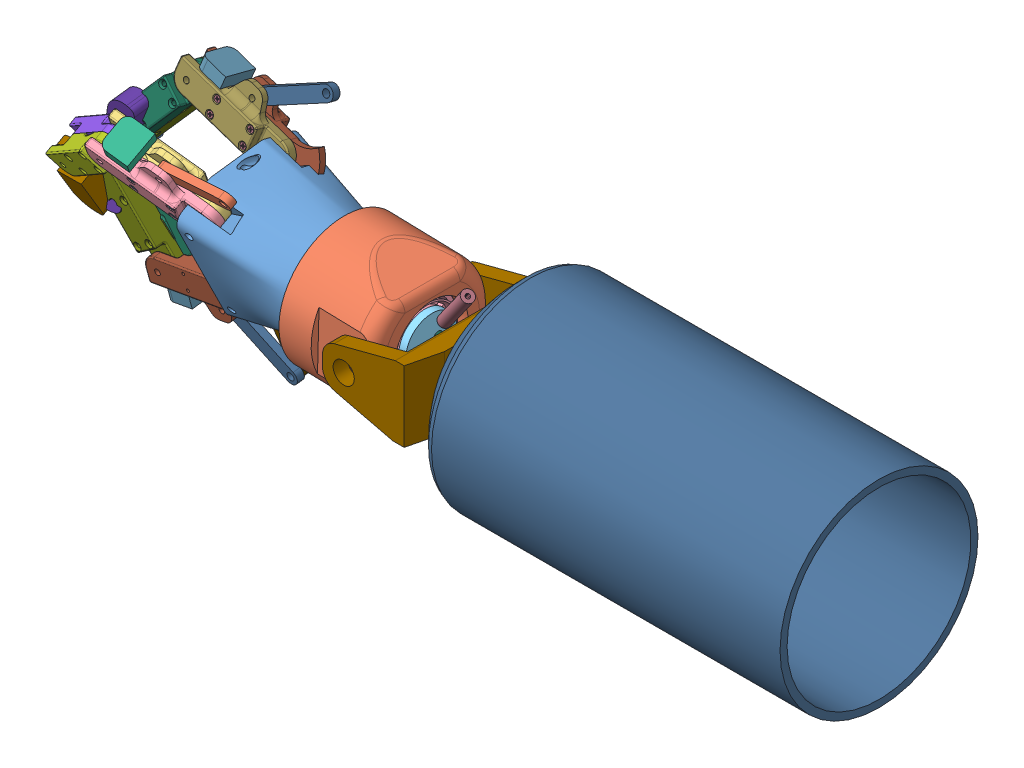
SolidWorks assembly Wrist-Rev1, configuration Default. Lengths in mm.
Overall size (584.91 244.28 159.91).
66 component instances, 31 part files, 5 mates.
Components (placement in the parent):
- handAssem^Wrist-Rev1-1: handAssem^Wrist-Rev1 [Default] at (-134.1215 -3.6591 -0.8911) x (0.999653 -0.026335 0) z (-0.003482 -0.132175 0.99122) size (188.44 172.28 105.92) (virtual)
  - Copy of hand^handAssem_Wrist-Rev1-1: Copy of hand^handAssem_Wrist-Rev1 [Default] at origin size (70.02 96.36 87.58) (virtual)
  - Copy of Finger^handAssem_Wrist-Rev1-1: Copy of Finger^handAssem_Wrist-Rev1 [Default] at (-63.4206 33.3683 25.4621) x (0.985078 0.159576 0.064473) z (0 -0.374607 0.927184) size (161.76 98.98 31.79) (virtual)
    - Part1^Copy of Finger_handAssem_Wrist-Rev1-1: Part1^Copy of Finger_handAssem_Wrist-Rev1 [Default] at (-16.5165 25.6409 -2) x (0.998962 0.045543 0) z (0 0 1) size (57.61 9.59 5) (virtual)
    - AssemFP3^Copy of Finger_handAssem_Wrist-Rev1-1: AssemFP3^Copy of Finger_handAssem_Wrist-Rev1 [Default] at (-63.9805 30.7815 -12) x (0.901133 -0.433542 0) z (0 0 1) size (80 31.95 25) (virtual)
      - Copy of SecondSideDoubleFP3^AssemFP3_Copy of Finger_handAssem_Wrist-Rev1-1: Copy of SecondSideDoubleFP3^AssemFP3_Copy of Finger_handAssem_Wrist-Rev1 [Default] at origin size (80 31.95 13.34) (virtual)
      - Copy of FirstSideDoubleFP3^AssemFP3_Copy of Finger_handAssem_Wrist-Rev1-1: Copy of FirstSideDoubleFP3^AssemFP3_Copy of Finger_handAssem_Wrist-Rev1 [Default] at (0 0 25) size (80 31.95 13.34) (virtual)
      - Copy of Self Tapping Cross recessed Screw 4Plastic^AssemFP3_Copy of Finger_handAssem_Wrist-Rev1-1: Copy of Self Tapping Cross recessed Screw 4Plastic^AssemFP3_Copy of Finger_handAssem_Wrist-Rev1 [Self Tap. Cross recessed Screw 2.6x16mm] at (30 -5.5 24.6) x (0 0 -1) z (0.511013 -0.859573 0) size (16 4.2 4.2) (virtual)
      - Copy of Self Tapping Cross recessed Screw 4Plastic^AssemFP3_Copy of Finger_handAssem_Wrist-Rev1-2: Copy of Self Tapping Cross recessed Screw 4Plastic^AssemFP3_Copy of Finger_handAssem_Wrist-Rev1 [Self Tap. Cross recessed Screw 2.6x16mm] at (30 4.7 24.6) x (0 0 -1) z (0.511013 -0.859573 0) size (16 4.2 4.2) (virtual)
      - Copy of Self Tapping Cross recessed Screw 4Plastic^AssemFP3_Copy of Finger_handAssem_Wrist-Rev1-3: Copy of Self Tapping Cross recessed Screw 4Plastic^AssemFP3_Copy of Finger_handAssem_Wrist-Rev1 [Self Tap. Cross recessed Screw 2.6x16mm] at (55.5 -5.5 24.6) x (0 0 -1) z (0.511013 -0.859573 0) size (16 4.2 4.2) (virtual)
      - Copy of Self Tapping Cross recessed Screw 4Plastic^AssemFP3_Copy of Finger_handAssem_Wrist-Rev1-4: Copy of Self Tapping Cross recessed Screw 4Plastic^AssemFP3_Copy of Finger_handAssem_Wrist-Rev1 [Self Tap. Cross recessed Screw 2.6x16mm] at (55.5 5.5 24.6) x (0 0 -1) z (0.511013 -0.859573 0) size (16 4.2 4.2) (virtual)
      - Copy of Part2^AssemFP3_Copy of Finger_handAssem_Wrist-Rev1-1: Copy of Part2^AssemFP3_Copy of Finger_handAssem_Wrist-Rev1 [Default] at (9.0118 9 22.7194) x (0.006732 0 -0.999977) z (0.999977 0 0.006732) size (22 8 19) (virtual)
    - AssemFP2^Copy of Finger_handAssem_Wrist-Rev1-1: AssemFP2^Copy of Finger_handAssem_Wrist-Rev1 [Default] at (-31.4624 86.5481 -31.1774) x (0.884286 0.466511 0.020138) z (-0.063233 0.076906 0.995031) size (81.78 27.56 27.59) (virtual)
      - Copy of FirstSideDoubleFP2^AssemFP2_Copy of Finger_handAssem_Wrist-Rev1-1: Copy of FirstSideDoubleFP2^AssemFP2_Copy of Finger_handAssem_Wrist-Rev1 [Default] at (-119.2204 -52.1061 42.2073) x (0.995783 0.091045 -0.011232) z (0.020138 -0.097506 0.995031) size (80 18.36 12.86) (virtual)
      - Copy of Copy of FirstSideDoubleFP2^AssemFP2_Copy of Finger_handAssem_Wrist-Rev1-1: Copy of Copy of FirstSideDoubleFP2^AssemFP2_Copy of Finger_handAssem_Wrist-Rev1 [Default] at (-119.7239 -49.6685 17.3316) x (0.995783 0.091045 -0.011232) z (0.020138 -0.097506 0.995031) size (80 18 12.5) (virtual)
    - AssemFP1^Copy of Finger_handAssem_Wrist-Rev1-1: AssemFP1^Copy of Finger_handAssem_Wrist-Rev1 [Default] at (-46.7906 101.0539 0) x (0.072186 0.997391 0) z (0 0 1) size (49.14 18 13.29) (virtual)
      - Copy of Part4^AssemFP1_Copy of Finger_handAssem_Wrist-Rev1-1: Copy of Part4^AssemFP1_Copy of Finger_handAssem_Wrist-Rev1 [Default] at (-121.6487 44.1587 14.7911) size (49.14 18 13.29) (virtual)
  - Copy (2) of Finger^handAssem_Wrist-Rev1-1: Copy (2) of Finger^handAssem_Wrist-Rev1 [Default] at (-65.476 37.9304 -28.3284) x (0.903748 0.396895 -0.160356) z (0 0.374607 0.927184) size (164.28 92.56 31.79) (virtual)
    - Part1^Copy (2) of Finger_handAssem_Wrist-Rev1-1: Part1^Copy (2) of Finger_handAssem_Wrist-Rev1 [Default] at (-10.8234 25.7812 -2.0514) x (0.998962 0.045543 0) z (0 0 1) size (57.61 9.59 5) (virtual)
    - AssemFP3^Copy (2) of Finger_handAssem_Wrist-Rev1-1: AssemFP3^Copy (2) of Finger_handAssem_Wrist-Rev1 [Default] at (-55.9504 41.3634 -12.0514) x (0.781947 -0.623344 0) z (0 0 1) size (96 40.28 25) (virtual)
      - Copy of SecondSideDoubleFP3^AssemFP3_Copy (2) of Finger_handAssem_Wrist-Rev1-1: Copy of SecondSideDoubleFP3^AssemFP3_Copy (2) of Finger_handAssem_Wrist-Rev1 [Default] at origin size (96 40.28 13.34) (virtual)
      - Copy of FirstSideDoubleFP3^AssemFP3_Copy (2) of Finger_handAssem_Wrist-Rev1-1: Copy of FirstSideDoubleFP3^AssemFP3_Copy (2) of Finger_handAssem_Wrist-Rev1 [Default] at (0 0 25) size (80 31.95 13.34) (virtual)
      - Copy of Self Tapping Cross recessed Screw 4Plastic^AssemFP3_Copy (2) of Finger_handAssem_Wrist-Rev1-1: Copy of Self Tapping Cross recessed Screw 4Plastic^AssemFP3_Copy (2) of Finger_handAssem_Wrist-Rev1 [Self Tap. Cross recessed Screw 2.6x16mm] at (30 -5.5 24.6) x (0 0 -1) z (0.511013 -0.859573 0) size (16 4.2 4.2) (virtual)
      - Copy of Self Tapping Cross recessed Screw 4Plastic^AssemFP3_Copy (2) of Finger_handAssem_Wrist-Rev1-2: Copy of Self Tapping Cross recessed Screw 4Plastic^AssemFP3_Copy (2) of Finger_handAssem_Wrist-Rev1 [Self Tap. Cross recessed Screw 2.6x16mm] at (30 4.7 24.6) x (0 0 -1) z (0.511013 -0.859573 0) size (16 4.2 4.2) (virtual)
      - Copy of Self Tapping Cross recessed Screw 4Plastic^AssemFP3_Copy (2) of Finger_handAssem_Wrist-Rev1-3: Copy of Self Tapping Cross recessed Screw 4Plastic^AssemFP3_Copy (2) of Finger_handAssem_Wrist-Rev1 [Self Tap. Cross recessed Screw 2.6x16mm] at (55.5 -5.5 24.6) x (0 0 -1) z (0.511013 -0.859573 0) size (16 4.2 4.2) (virtual)
      - Copy of Self Tapping Cross recessed Screw 4Plastic^AssemFP3_Copy (2) of Finger_handAssem_Wrist-Rev1-4: Copy of Self Tapping Cross recessed Screw 4Plastic^AssemFP3_Copy (2) of Finger_handAssem_Wrist-Rev1 [Self Tap. Cross recessed Screw 2.6x16mm] at (55.5 5.5 24.6) x (0 0 -1) z (0.511013 -0.859573 0) size (16 4.2 4.2) (virtual)
      - Copy of Part2^AssemFP3_Copy (2) of Finger_handAssem_Wrist-Rev1-1: Copy of Part2^AssemFP3_Copy (2) of Finger_handAssem_Wrist-Rev1 [Default] at (9.0118 9 22.7194) x (0.006732 0 -0.999977) z (0.999977 0 0.006732) size (22 8 19) (virtual)
    - AssemFP2^Copy (2) of Finger_handAssem_Wrist-Rev1-1: AssemFP2^Copy (2) of Finger_handAssem_Wrist-Rev1 [Default] at (-18.1675 92.417 -31.2288) x (0.929732 0.367687 0.020138) z (-0.054504 0.083321 0.995031) size (81.78 27.56 27.59) (virtual)
      - Copy of FirstSideDoubleFP2^AssemFP2_Copy (2) of Finger_handAssem_Wrist-Rev1-1: Copy of FirstSideDoubleFP2^AssemFP2_Copy (2) of Finger_handAssem_Wrist-Rev1 [Default] at (-119.2204 -52.1061 42.2073) x (0.995783 0.091045 -0.011232) z (0.020138 -0.097506 0.995031) size (80 18.36 12.86) (virtual)
      - Copy of Copy of FirstSideDoubleFP2^AssemFP2_Copy (2) of Finger_handAssem_Wrist-Rev1-1: Copy of Copy of FirstSideDoubleFP2^AssemFP2_Copy (2) of Finger_handAssem_Wrist-Rev1 [Default] at (-119.7239 -49.6685 17.3316) x (0.995783 0.091045 -0.011232) z (0.020138 -0.097506 0.995031) size (80 18 12.5) (virtual)
    - AssemFP1^Copy (2) of Finger_handAssem_Wrist-Rev1-1: AssemFP1^Copy (2) of Finger_handAssem_Wrist-Rev1 [Default] at (-27.2302 105.0249 -0.0514) x (0.225639 0.974211 0) z (0 0 1) size (49.14 18 13.29) (virtual)
      - Copy of Part4^AssemFP1_Copy (2) of Finger_handAssem_Wrist-Rev1-1: Copy of Part4^AssemFP1_Copy (2) of Finger_handAssem_Wrist-Rev1 [Default] at (-121.6487 44.1587 14.7911) size (49.14 18 13.29) (virtual)
  - Copy (2) of Finger^handAssem_Wrist-Rev1-2: Copy (2) of Finger^handAssem_Wrist-Rev1 [Default] at (-64.0753 -41.2434 0.4486) x (0.9011 -0.433611 0) z (0 0 -1) size (164.28 92.56 31.79) (virtual)
    - Part1^Copy (2) of Finger_handAssem_Wrist-Rev1-1: Part1^Copy (2) of Finger_handAssem_Wrist-Rev1 [Default] at (-10.8234 25.7812 -2.0514) x (0.998962 0.045543 0) z (0 0 1) size (57.61 9.59 5) (virtual)
    - AssemFP3^Copy (2) of Finger_handAssem_Wrist-Rev1-1: AssemFP3^Copy (2) of Finger_handAssem_Wrist-Rev1 [Default] at (-55.9504 41.3634 -12.0514) x (0.781947 -0.623344 0) z (0 0 1) size (96 40.28 25) (virtual)
      - Copy of SecondSideDoubleFP3^AssemFP3_Copy (2) of Finger_handAssem_Wrist-Rev1-1: Copy of SecondSideDoubleFP3^AssemFP3_Copy (2) of Finger_handAssem_Wrist-Rev1 [Default] at origin size (96 40.28 13.34) (virtual)
      - Copy of FirstSideDoubleFP3^AssemFP3_Copy (2) of Finger_handAssem_Wrist-Rev1-1: Copy of FirstSideDoubleFP3^AssemFP3_Copy (2) of Finger_handAssem_Wrist-Rev1 [Default] at (0 0 25) size (80 31.95 13.34) (virtual)
      - Copy of Self Tapping Cross recessed Screw 4Plastic^AssemFP3_Copy (2) of Finger_handAssem_Wrist-Rev1-1: Copy of Self Tapping Cross recessed Screw 4Plastic^AssemFP3_Copy (2) of Finger_handAssem_Wrist-Rev1 [Self Tap. Cross recessed Screw 2.6x16mm] at (30 -5.5 24.6) x (0 0 -1) z (0.511013 -0.859573 0) size (16 4.2 4.2) (virtual)
      - Copy of Self Tapping Cross recessed Screw 4Plastic^AssemFP3_Copy (2) of Finger_handAssem_Wrist-Rev1-2: Copy of Self Tapping Cross recessed Screw 4Plastic^AssemFP3_Copy (2) of Finger_handAssem_Wrist-Rev1 [Self Tap. Cross recessed Screw 2.6x16mm] at (30 4.7 24.6) x (0 0 -1) z (0.511013 -0.859573 0) size (16 4.2 4.2) (virtual)
      - Copy of Self Tapping Cross recessed Screw 4Plastic^AssemFP3_Copy (2) of Finger_handAssem_Wrist-Rev1-3: Copy of Self Tapping Cross recessed Screw 4Plastic^AssemFP3_Copy (2) of Finger_handAssem_Wrist-Rev1 [Self Tap. Cross recessed Screw 2.6x16mm] at (55.5 -5.5 24.6) x (0 0 -1) z (0.511013 -0.859573 0) size (16 4.2 4.2) (virtual)
      - Copy of Self Tapping Cross recessed Screw 4Plastic^AssemFP3_Copy (2) of Finger_handAssem_Wrist-Rev1-4: Copy of Self Tapping Cross recessed Screw 4Plastic^AssemFP3_Copy (2) of Finger_handAssem_Wrist-Rev1 [Self Tap. Cross recessed Screw 2.6x16mm] at (55.5 5.5 24.6) x (0 0 -1) z (0.511013 -0.859573 0) size (16 4.2 4.2) (virtual)
      - Copy of Part2^AssemFP3_Copy (2) of Finger_handAssem_Wrist-Rev1-1: Copy of Part2^AssemFP3_Copy (2) of Finger_handAssem_Wrist-Rev1 [Default] at (9.0118 9 22.7194) x (0.006732 0 -0.999977) z (0.999977 0 0.006732) size (22 8 19) (virtual)
    - AssemFP2^Copy (2) of Finger_handAssem_Wrist-Rev1-1: AssemFP2^Copy (2) of Finger_handAssem_Wrist-Rev1 [Default] at (-18.1675 92.417 -31.2288) x (0.929732 0.367687 0.020138) z (-0.054504 0.083321 0.995031) size (81.78 27.56 27.59) (virtual)
      - Copy of FirstSideDoubleFP2^AssemFP2_Copy (2) of Finger_handAssem_Wrist-Rev1-1: Copy of FirstSideDoubleFP2^AssemFP2_Copy (2) of Finger_handAssem_Wrist-Rev1 [Default] at (-119.2204 -52.1061 42.2073) x (0.995783 0.091045 -0.011232) z (0.020138 -0.097506 0.995031) size (80 18.36 12.86) (virtual)
      - Copy of Copy of FirstSideDoubleFP2^AssemFP2_Copy (2) of Finger_handAssem_Wrist-Rev1-1: Copy of Copy of FirstSideDoubleFP2^AssemFP2_Copy (2) of Finger_handAssem_Wrist-Rev1 [Default] at (-119.7239 -49.6685 17.3316) x (0.995783 0.091045 -0.011232) z (0.020138 -0.097506 0.995031) size (80 18 12.5) (virtual)
    - AssemFP1^Copy (2) of Finger_handAssem_Wrist-Rev1-1: AssemFP1^Copy (2) of Finger_handAssem_Wrist-Rev1 [Default] at (-27.2302 105.0249 -0.0514) x (0.225639 0.974211 0) z (0 0 1) size (49.14 18 13.29) (virtual)
      - Copy of Part4^AssemFP1_Copy (2) of Finger_handAssem_Wrist-Rev1-1: Copy of Part4^AssemFP1_Copy (2) of Finger_handAssem_Wrist-Rev1 [Default] at (-121.6487 44.1587 14.7911) size (49.14 18 13.29) (virtual)
  - Copy (2) of lever^handAssem_Wrist-Rev1-3: Copy (2) of lever^handAssem_Wrist-Rev1 [Default] at (-57.1688 -55.6953 -2.5) x (0.880705 0.473665 0) z (-0.473665 0.880705 0) size (24.52 5 37.7) (virtual)
  - Copy of Part1^handAssem_Wrist-Rev1-1: Copy of Part1^handAssem_Wrist-Rev1 [Default] at (-184.8247 -12.0126 -28.3954) x (1 0 0) z (0 1 0) size (27.2 5 7.2) (virtual)
- RotationUnit-1: RotationUnit [Default] at (-102.2058 -4.4999 -0.8911) x (0.999653 -0.026335 0) z (0.026335 0.999653 0) size (79.33 94.5 90)
  - rotatingPart^RotationUnit-1: rotatingPart^RotationUnit [Default] at origin size (63.63 90 90) (virtual)
  - Copy of axis^RotationUnit-1: Copy of axis^RotationUnit [Default] at (-47.25 0 0) x (1 0 0) z (0 -0.2761 0.961129) size (73 36 36) (virtual)
  - 6677K87_Tapered-Roller Bearing with Steel Ring-1: 6677K87_Tapered-Roller Bearing with Steel Ring [6677K87] at (16.5 0 0) x (0 0.225972 0.974134) z (-1 0 0) size (52 52 19.81)
  - 6677K87_Tapered-Roller Bearing with Steel Ring-2: 6677K87_Tapered-Roller Bearing with Steel Ring [6677K87] at (-16.5 0 0) x (0 0 1) z (1 0 0) size (52 52 19.81)
  - Part1^RotationUnit-1: Part1^RotationUnit [Default] at (26.25 0 0) x (0 -0.2761 0.961129) z (0 0.961129 0.2761) size (36 5 36) (virtual)
  - 92125A130_18-8 Stainless Steel Hex Drive Flat Head Screw-1: 92125A130_18-8 Stainless Steel Hex Drive Flat Head Screw [92125A130] at (26.335 -4.8056 -1.3805) x (0 0 -1) z (1 0 0) size (6 6 10.3)
  - 92125A130_18-8 Stainless Steel Hex Drive Flat Head Screw-2: 92125A130_18-8 Stainless Steel Hex Drive Flat Head Screw [92125A130] at (26.185 4.8056 1.3805) x (0 0 -1) z (1 0 0) size (6 6 10.3)
  - Part2^RotationUnit-1: Part2^RotationUnit [Default] at (19.2645 38.5 0) x (0 -1 0) z (0 0 1) size (22 8 8) (virtual)
  - 90154A137_External Retaining Ring-1: 90154A137_External Retaining Ring [90154A137] at (19.2645 38.375 0) x (0.995938 0 -0.090045) z (0 -1 0) size (9.68 12.1 0.75)
- Ujoint^Wrist-Rev1-1: Ujoint^Wrist-Rev1 [Default] at (-47.948 20.6692 -0.8911) x (1 0 0) z (0 0 -1) size (63.31 50 100) (virtual)
- handEnclosure^Wrist-Rev1-2: handEnclosure^Wrist-Rev1 [Default] at origin size (287.08 140 140) (virtual)
- frictionInsert^Wrist-Rev1-1: frictionInsert^Wrist-Rev1 [Default] at (-82.948 -5.0073 -40.8911) x (0 0 -1) z (0.945769 0.324839 0) size (10 15 15) (virtual)
- wheel^Wrist-Rev1-1: wheel^Wrist-Rev1 [Default] at (-105.9728 14.6056 -33.2941) size (15 14 14) (virtual)
- wheel^Wrist-Rev1-2: wheel^Wrist-Rev1 [Default] at (-106.6786 -23.4544 -33.0575) size (15 14 14) (virtual)
- Part2^Wrist-Rev1-1: Part2^Wrist-Rev1 [Default] at (-47.7798 26.1691 13.2935) x (0.602026 0.777459 0.181997) z (-0.543122 0.231637 0.807071) size (40 8 8) (virtual)
- Part2^Wrist-Rev1-2: Part2^Wrist-Rev1 [Default] at (-48.0548 -33.9848 -11.1568) x (0.677349 -0.699006 -0.229323) z (0.626799 0.38517 0.677324) size (40 8 8) (virtual)
Mates (geometry in assembly coordinates):
- Coincident8: coincident aligned: plane of Ujoint^Wrist-Rev1-1 through (-97.948 -29.3308 -50.8911) normal (0 0 -1); plane of Part4^Wrist-Rev1-1 through (-84.2799 -1.1296 -50.8911) normal (0 0 -1)
- Concentric9: concentric aligned: cylinder of Ujoint^Wrist-Rev1-1 through (-82.948 -5.0073 49.1089) axis (0 0 -1) radius 7.5; cylinder of Part4^Wrist-Rev1-1 through (-82.948 -5.0073 -40.8911) axis (0 0 -1) radius 7.5
- Concentric10: concentric anti-aligned: cylinder of RotationUnit^Wrist-Rev1-1/Part2^RotationUnit_Wrist-Rev1-1 through (-82.948 -5.0073 -28.3911) axis (0 0 1) radius 4; cylinder of Part4^Wrist-Rev1-1 through (-82.948 -5.0073 -40.8911) axis (0 0 -1) radius 4.1
- Coincident9: coincident anti-aligned: plane of RotationUnit^Wrist-Rev1-1/rotatingPart^Assem1_Wrist-Rev1-1 through (-60.7051 -50.6089 39.1089) normal (0 0 1); plane of Ujoint^Wrist-Rev1-1 through (-97.948 -29.3308 39.1089) normal (0 0 -1)
- Concentric12: concentric anti-aligned: cylinder of handAssem^Wrist-Rev1-1/Copy of hand^Assem1_Wrist-Rev1-1 through (-144.118 -3.3958 -0.8911) axis (0.999653 -0.026335 0) radius 18.1; cylinder of RotationUnit^Wrist-Rev1-1/Copy of axis^RotationUnit_Wrist-Rev1-1 through (-149.4395 -3.2556 -0.8911) axis (-0.999653 0.026335 0) radius 18
